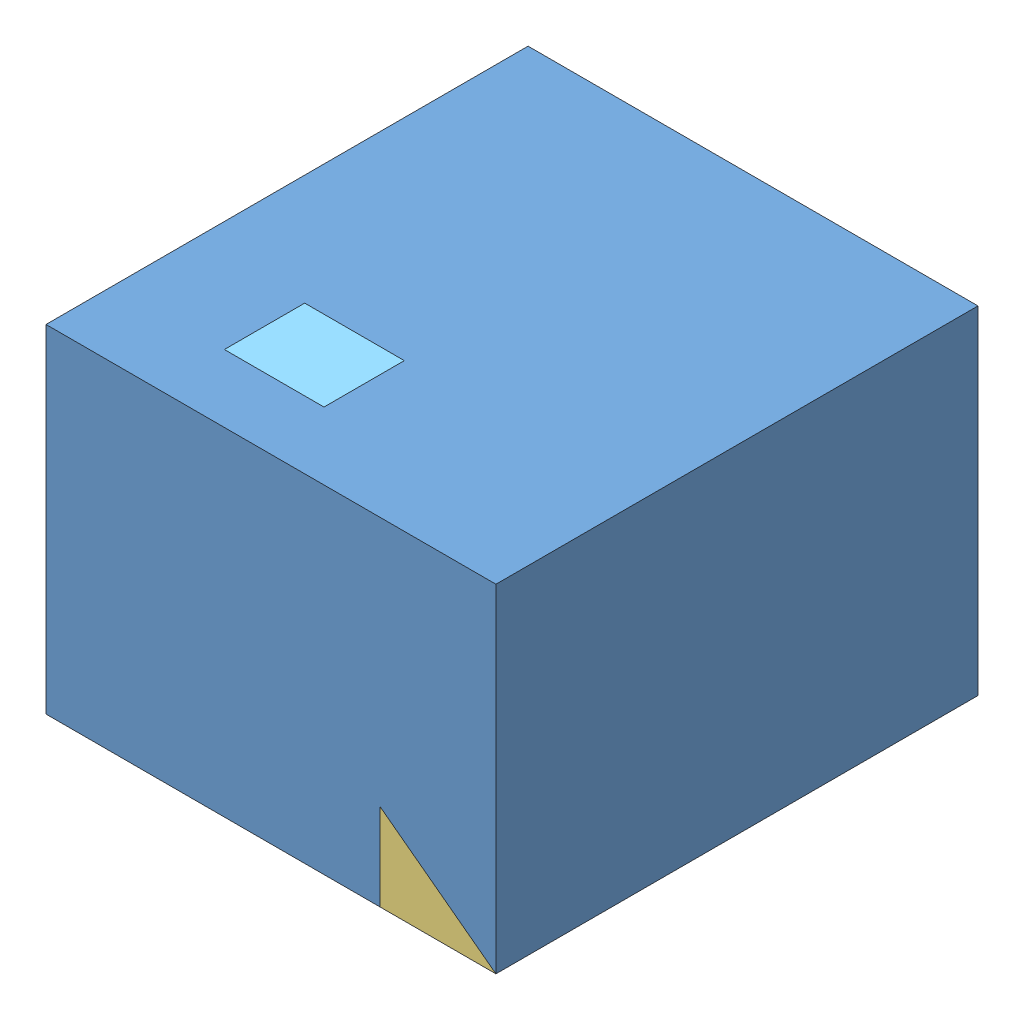
SolidWorks assembly layoutPlan, configuration Default. Lengths in mm.
Overall size (280 210 300).
11 component instances, 5 part files, 29 mates.
Components (placement in the parent):
- rover^layoutPlan-1: rover^layoutPlan [Default] at origin size (280 210 300) (virtual)
- body^layoutPlan-1: body^layoutPlan [Default] at (72 0 -39) size (136 46 190) (virtual)
- suspension^layoutPlan-1: suspension^layoutPlan [Default] at (-208 0 0) x (-1 0 0) z (0 -1 0) size (72 271 122) (virtual)
- wheel^layoutPlan-1: wheel^layoutPlan [Default] at (0 0 -92.6961) x (-1 0 0) z (0 -1 0) size (40 50 50) (virtual)
- mast^layoutPlan-1: mast^layoutPlan [Default] at (69 112 -42) x (1 0 0) z (0 1 0) size (62 50 98) (virtual)
- suspension^layoutPlan-2: suspension^layoutPlan [Default] x (-1 0 0) z (0 -1 0) size (72 271 122) (virtual)
- wheel^layoutPlan-2: wheel^layoutPlan [Default] at (5 0 -221) x (-1 0 0) z (0 -1 0) size (40 50 50) (virtual)
- wheel^layoutPlan-3: wheel^layoutPlan [Default] at (235 0 -221) x (-1 0 0) z (0 -1 0) size (40 50 50) (virtual)
- wheel^layoutPlan-4: wheel^layoutPlan [Default] at (235 0 0) x (-1 0 0) z (0 -1 0) size (40 50 50) (virtual)
- wheel^layoutPlan-5: wheel^layoutPlan [Default] at (5 0 0) x (-1 0 0) z (0 -1 0) size (40 50 50) (virtual)
- wheel^layoutPlan-6: wheel^layoutPlan [Default] at (240 0 -92.6961) x (-1 0 0) z (0 -1 0) size (40 50 50) (virtual)
Mates (geometry in assembly coordinates):
- Coincident10: coincident aligned: plane of rover^layoutPlan-1 through (0 0 0) normal (0 -1 0); plane of wheel^layoutPlan-6 through (240 0 -92.6961) normal (0 -1 0)
- Coincident11: coincident aligned: plane of rover^layoutPlan-1 through (0 0 0) normal (0 -1 0); plane of wheel^layoutPlan-3 through (235 0 -221) normal (0 -1 0)
- Coincident12: coincident aligned: plane of rover^layoutPlan-1 through (0 0 0) normal (0 -1 0); plane of wheel^layoutPlan-2 through (5 0 -221) normal (0 -1 0)
- Coincident13: coincident aligned: plane of rover^layoutPlan-1 through (0 0 0) normal (0 -1 0); plane of wheel^layoutPlan-4 through (235 0 0) normal (0 -1 0)
- Coincident14: coincident aligned: plane of rover^layoutPlan-1 through (0 0 0) normal (0 -1 0); plane of wheel^layoutPlan-1 through (0 0 -92.6961) normal (0 -1 0)
- Coincident15: coincident aligned: plane of rover^layoutPlan-1 through (0 0 0) normal (0 -1 0); plane of wheel^layoutPlan-5 through (5 0 0) normal (0 -1 0)
- Coincident16: coincident aligned: plane of rover^layoutPlan-1 through (0 0 0) normal (0 -1 0); plane of suspension^layoutPlan-2 through (0 0 0) normal (0 -1 0)
- Coincident17: coincident aligned: plane of rover^layoutPlan-1 through (0 0 0) normal (0 -1 0); plane of suspension^layoutPlan-1 through (-208 0 0) normal (0 -1 0)
- Coincident18: coincident aligned: plane of rover^layoutPlan-1 through (280 210 0) normal (1 0 0); plane of suspension^layoutPlan-2 through (280 122 0) normal (1 0 0)
- Coincident19: coincident aligned: plane of rover^layoutPlan-1 through (0 210 0) normal (-1 0 0); plane of suspension^layoutPlan-1 through (0 122 0) normal (-1 0 0)
- Coincident20: coincident aligned: plane of rover^layoutPlan-1 through (0 210 0) normal (0 0 1); plane of suspension^layoutPlan-2 through (280 122 0) normal (0 0 1)
- Coincident21: coincident aligned: plane of rover^layoutPlan-1 through (0 210 0) normal (0 0 1); plane of suspension^layoutPlan-1 through (72 122 0) normal (0 0 1)
- Coincident22: coincident aligned: plane of suspension^layoutPlan-1 through (72 122 0) normal (0 0 1); plane of wheel^layoutPlan-5 through (5 50 0) normal (0 0 1)
- Distance1: distance = 5 mm aligned: plane of wheel^layoutPlan-5 through (5 50 0) normal (-1 0 0); plane of suspension^layoutPlan-1 through (0 122 0) normal (-1 0 0)
- Coincident24: coincident aligned: plane of suspension^layoutPlan-1 through (72 122 -271) normal (0 0 -1); plane of wheel^layoutPlan-2 through (5 50 -271) normal (0 0 -1)
- Distance2: distance = 5 mm aligned: plane of wheel^layoutPlan-2 through (5 50 -221) normal (-1 0 0); plane of suspension^layoutPlan-1 through (0 122 0) normal (-1 0 0)
- Coincident26: coincident aligned: plane of suspension^layoutPlan-1 through (0 122 0) normal (-1 0 0); plane of wheel^layoutPlan-1 through (0 50 -92.6961) normal (-1 0 0)
- Coincident27: coincident aligned: plane of suspension^layoutPlan-2 through (280 122 0) normal (0 0 1); plane of wheel^layoutPlan-4 through (235 50 0) normal (0 0 1)
- Distance3: distance = 5 mm aligned: plane of wheel^layoutPlan-4 through (275 50 0) normal (1 0 0); plane of suspension^layoutPlan-2 through (280 122 0) normal (1 0 0)
- Coincident29: coincident aligned: plane of suspension^layoutPlan-2 through (280 122 -271) normal (0 0 -1); plane of wheel^layoutPlan-3 through (235 50 -271) normal (0 0 -1)
- Distance4: distance = 5 mm aligned: plane of wheel^layoutPlan-3 through (275 50 -221) normal (1 0 0); plane of suspension^layoutPlan-2 through (280 122 0) normal (1 0 0)
- Coincident31: coincident aligned: plane of suspension^layoutPlan-2 through (280 122 0) normal (1 0 0); plane of wheel^layoutPlan-6 through (280 50 -92.6961) normal (1 0 0)
- Coincident32: coincident aligned: plane of wheel^layoutPlan-1 through (0 50 -142.6961) normal (0 0 -1); plane of wheel^layoutPlan-6 through (240 50 -142.6961) normal (0 0 -1)
- Coincident33: coincident anti-aligned: plane of body^layoutPlan-1 through (208 112 -39) normal (1 0 0); plane of suspension^layoutPlan-2 through (208 122 0) normal (-1 0 0)
- Distance5: distance = 66 mm aligned: plane of body^layoutPlan-1 through (72 66 -39) normal (0 -1 0); plane of rover^layoutPlan-1 through (0 0 0) normal (0 -1 0)
- Distance6: distance = 39 mm aligned: plane of body^layoutPlan-1 through (72 112 -39) normal (0 0 1); plane of suspension^layoutPlan-2 through (280 122 0) normal (0 0 1)
- Coincident36: coincident anti-aligned: plane of body^layoutPlan-1 through (72 112 -39) normal (0 1 0); plane of mast^layoutPlan-1 through (69 112 -42) normal (0 -1 0)
- Distance9: distance = 28 mm: point of mast^layoutPlan-1; line of body^layoutPlan-1 through (72 112 -39) axis (1 0 0)
- Distance10: distance = 28 mm: point of mast^layoutPlan-1; line of body^layoutPlan-1 through (72 112 -229) axis (0 0 1)
